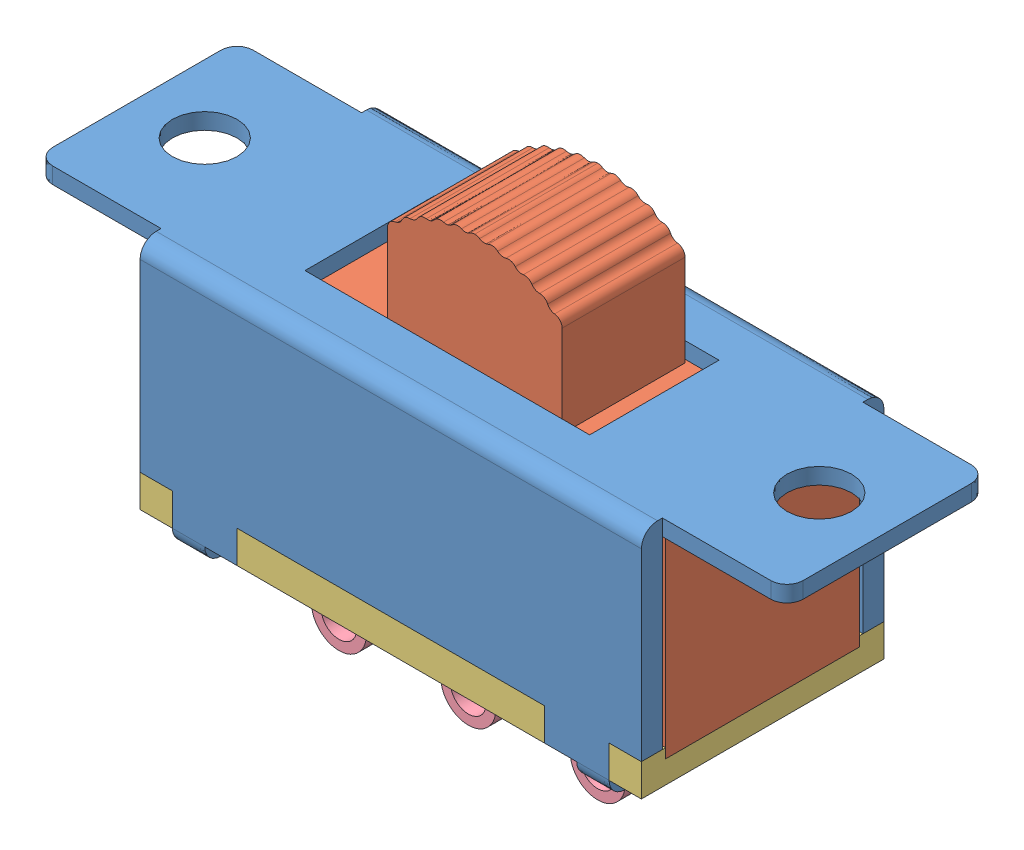
SolidWorks assembly slide switch, configuration Default. Lengths in mm.
Overall size (23.2 13.8 7.5).
9 component instances, 4 part files, 26 mates.
Components (placement in the parent):
- Slide switch shell-1: Slide switch shell [Default] at (9.4004 15.6952 14.9795) size (23.2 7.7 7.5)
- switch lever-1: switch lever [Default] at (10.1504 9.1952 14.9795) size (14 10 6)
- PCB-1: PCB [Default] at (9.4004 8.4952 14.9795) size (15.5 1 7.5)
- Pin-1: Pin [Default] at (13.4004 6.2452 15.8295) size (1.7 3.1 0.5)
- Pin-2: Pin [Default] at (9.4004 6.2452 15.8295) size (1.7 3.1 0.5)
- Pin-3: Pin [Default] at (5.4004 6.2452 15.8295) size (1.7 3.1 0.5)
- Pin-4: Pin [Default] at (13.4004 6.2452 13.1295) size (1.7 3.1 0.5)
- Pin-5: Pin [Default] at (5.4004 6.2452 13.1295) size (1.7 3.1 0.5)
- Pin-6: Pin [Default] at (9.4004 6.2452 13.1295) size (1.7 3.1 0.5)
Mates (geometry in assembly coordinates):
- Coincident1: coincident anti-aligned: plane of Slide switch shell-1 through (9.4004 15.1952 14.9795) normal (0 -1 0); plane of switch lever-1 through (10.1504 15.1952 14.9795) normal (0 1 0)
- Distance1: distance = 0.1 mm anti-aligned: plane of switch lever-1 through (3.1504 15.1952 17.9795) normal (0 0 1); plane of Slide switch shell-1 through (1.6504 9.4952 18.0795) normal (0 0 -1)
- Distance2: distance = 0 mm aligned: plane of switch lever-1 through (17.1504 15.1952 11.9795) normal (1 0 0); plane of Slide switch shell-1 through (17.1504 15.1952 14.9795) normal (1 0 0)
- Coincident4: coincident anti-aligned: plane of Slide switch shell-1 through (9.4004 9.4952 14.9795) normal (0 -1 0); plane of PCB-1 through (9.4004 9.4952 14.9795) normal (0 1 0)
- Coincident5: coincident aligned: plane of Slide switch shell-1 through (9.4004 15.1952 11.2295) normal (0 0 -1); plane of PCB-1 through (4.6504 9.4952 11.2295) normal (0 0 -1)
- Coincident6: coincident aligned: plane of Slide switch shell-1 through (17.1504 15.1952 14.9795) normal (1 0 0); plane of PCB-1 through (17.1504 9.4952 11.2295) normal (1 0 0)
- Parallel2: parallel aligned: plane of Slide switch shell-1 through (9.4004 15.1952 18.7295) normal (0 0 1); plane of Pin-1 through (13.4004 6.2452 17.29) normal (0 0 1)
- Coincident11: coincident anti-aligned: plane of PCB-1 through (9.4004 8.4952 14.9795) normal (0 -1 0); plane of Pin-1 through (12.5504 8.4952 17.29) normal (0 1 0)
- Distance7: distance = 3.15 mm: plane of Pin-1 through (12.5504 8.4952 16.3295) normal (-1 0 0); moEndPointRef_w of PCB-1
- Parallel3: parallel aligned: plane of Slide switch shell-1 through (9.4004 15.1952 18.7295) normal (0 0 1); plane of Pin-2 through (9.4004 6.2452 17.29) normal (0 0 1)
- Coincident19: coincident anti-aligned: plane of PCB-1 through (9.4004 8.4952 14.9795) normal (0 -1 0); plane of Pin-2 through (8.5504 8.4952 17.29) normal (0 1 0)
- Coincident20: coincident aligned: plane of Pin-1 through (13.4004 6.2452 17.29) normal (0 0 1); plane of Pin-2 through (9.4004 6.2452 17.29) normal (0 0 1)
- Distance8: distance = 4 mm: moEndPointRef_w of Pin-2; moEndPointRef_w of Pin-1
- Coincident23: coincident aligned: plane of Pin-4 through (12.5504 8.4952 14.59) normal (0 1 0); plane of Pin-6 through (8.5504 8.4952 14.59) normal (0 1 0)
- Coincident24: coincident aligned: plane of Pin-3 through (4.5504 8.4952 17.29) normal (0 1 0); plane of Pin-6 through (8.5504 8.4952 14.59) normal (0 1 0)
- Coincident25: coincident aligned: plane of Pin-3 through (4.5504 8.4952 17.29) normal (0 1 0); plane of Pin-5 through (4.5504 8.4952 14.59) normal (0 1 0)
- Coincident26: coincident aligned: plane of Pin-4 through (13.4004 6.2452 14.59) normal (0 0 1); plane of Pin-6 through (9.4004 6.2452 14.59) normal (0 0 1)
- Coincident27: coincident aligned: plane of Pin-5 through (5.4004 6.2452 14.59) normal (0 0 1); plane of Pin-6 through (9.4004 6.2452 14.59) normal (0 0 1)
- Coincident28: coincident anti-aligned: plane of PCB-1 through (9.4004 8.4952 14.9795) normal (0 -1 0); plane of Pin-4 through (12.5504 8.4952 14.59) normal (0 1 0)
- Coincident29: coincident aligned: plane of Pin-1 through (14.2504 8.4952 17.29) normal (1 0 0); plane of Pin-4 through (14.2504 8.4952 14.59) normal (1 0 0)
- Coincident30: coincident aligned: plane of Pin-2 through (10.2504 8.4952 17.29) normal (1 0 0); plane of Pin-6 through (10.2504 8.4952 14.59) normal (1 0 0)
- Coincident31: coincident aligned: plane of Pin-1 through (13.4004 6.2452 17.29) normal (0 0 1); plane of Pin-3 through (5.4004 6.2452 17.29) normal (0 0 1)
- Coincident32: coincident aligned: plane of Pin-3 through (6.2504 8.4952 17.29) normal (1 0 0); plane of Pin-5 through (6.2504 8.4952 14.59) normal (1 0 0)
- Distance9: distance = 4 mm: moEndPointRef_w of Pin-3; moEndPointRef_w of Pin-2
- Distance10: distance = 2.7 mm: moEndPointRef_w of Pin-2; moEndPointRef_w of Pin-6
- Distance11: distance = 2.4 mm aligned: plane of Pin-1 through (13.4004 6.2452 16.3295) normal (0 0 1); plane of Slide switch shell-1 through (9.4004 15.1952 18.7295) normal (0 0 1)
